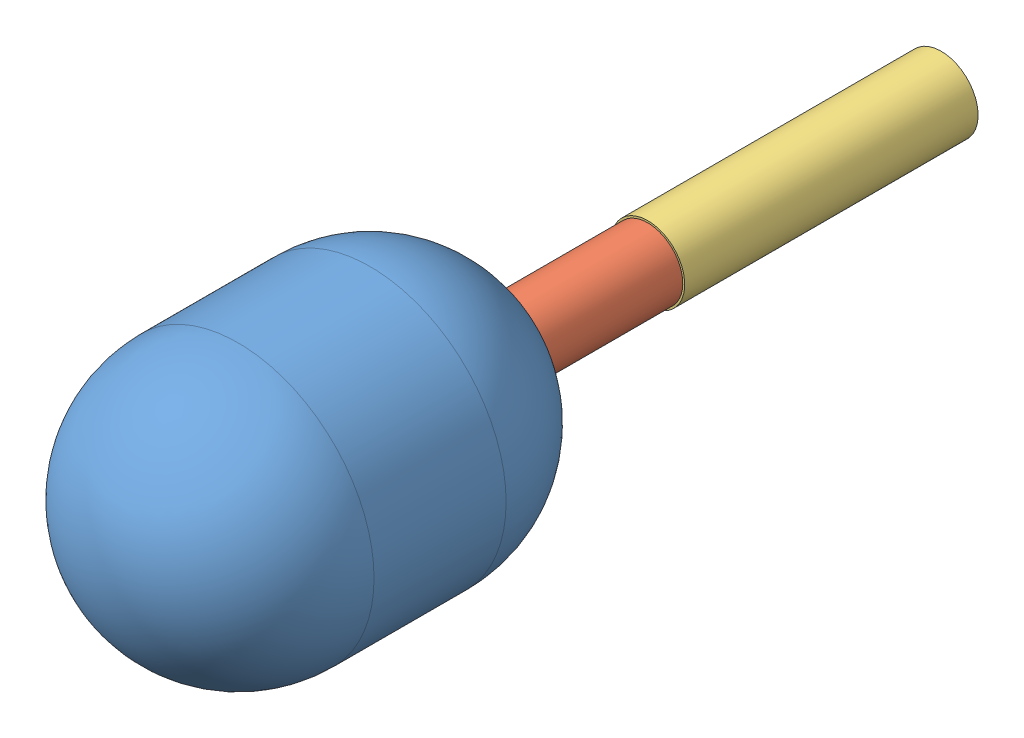
SolidWorks assembly LoFi Tank+Reg, configuration Default. Lengths in mm.
Overall size (111.12 111.12 342.9).
3 component instances, 3 part files, 8 mates.
Components (placement in the parent):
- LoFi Tank-1: LoFi Tank [Default] at origin size (111.12 111.12 163.23)
- LoFi Reg 1-1: LoFi Reg 1 [Default] at (0 0 -80.6816) x (-0.38598 0.922507 0) z (-0.922507 -0.38598 0) size (28.57 59.78 28.57)
- LoFi Reg 2-1: LoFi Reg 2 [Default] at (0 0 -140.462) x (-0.99247 0.12249 0) z (-0.12249 -0.99247 0) size (31.75 119.89 31.75)
Mates (geometry in assembly coordinates):
- Coincident3: coincident aligned: circle of LoFi Reg 1-1; circle of LoFi Tank-1
- Coincident2: coincident anti-aligned: plane of LoFi Reg 1-1 through (0 0 -140.462) normal (0 0 -1); plane of LoFi Reg 2-1 through (0 0 -140.462) normal (0 0 1)
- Concentric2: concentric aligned: circle of LoFi Reg 1-1; circle of LoFi Reg 2-1
- Concentric4: concentric: sphere of LoFi Tank-1
- Coincident7: coincident aligned: circle of LoFi Tank-1
- Coincident12: coordinate: unknown of LoFi Tank-1
- Lock1: lock: unknown of LoFi Tank-1; unknown of LoFi Reg 1-1
- Concentric5: concentric aligned: cylinder of LoFi Reg 1-1 through (0 0 -140.462) axis (0 0 1) radius 14.2875; cylinder of LoFi Reg 2-1 through (0 0 -260.35) axis (0 0 1) radius 15.875
